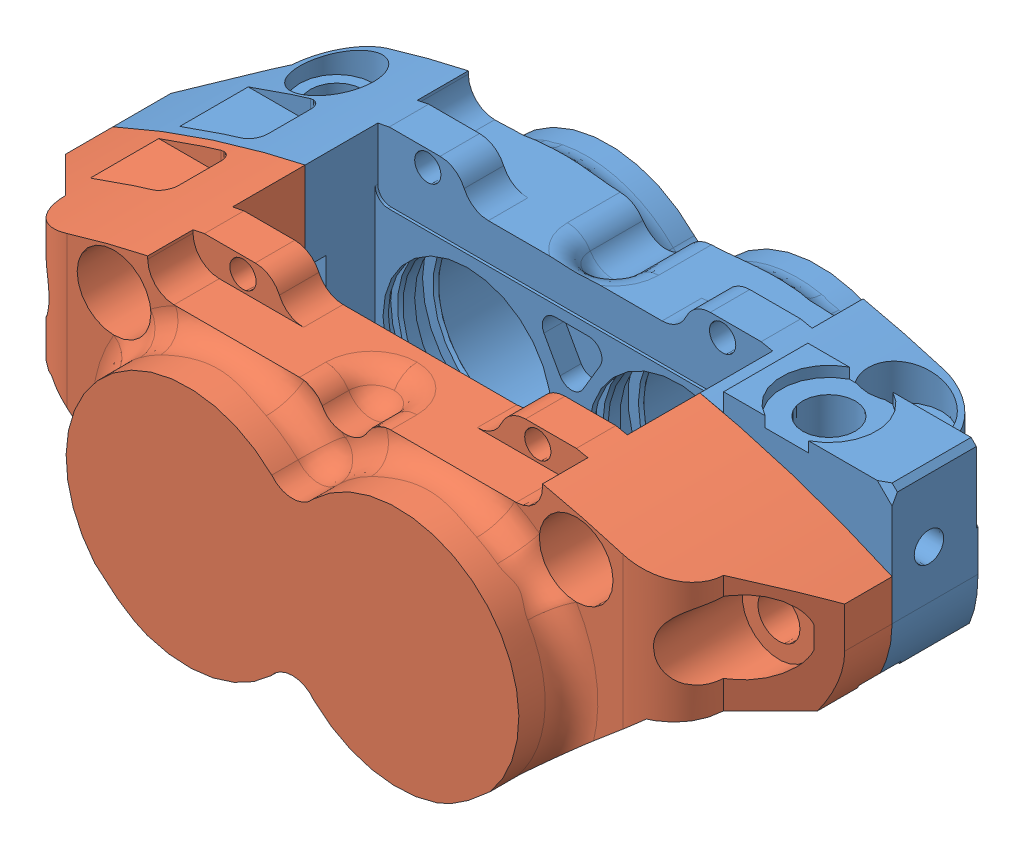
SolidWorks assembly Assemblage1, configuration Défaut. Lengths in mm.
Overall size (148 56.5 79.9).
2 component instances, 2 part files, 3 mates.
Components (placement in the parent):
- coté gauche-1: coté gauche [Défaut] at (-14.402 -5.9455 106) size (148 56.5 40)
- coté droit-1: coté droit [coté droit] at (-14.402 -5.9455 106) size (148 54.5 39.9)
Mates (geometry in assembly coordinates):
- Coaxiale1: concentric anti-aligned: cylinder of coté gauche-1 through (-58.2097 15.322 106) axis (0 0 1) radius 2.5; cylinder of coté droit-1 through (-58.2097 15.322 190) axis (0 0 -1) radius 2.5
- Coaxiale2: concentric aligned: cylinder of coté gauche-1 through (-74.1097 8.622 130) axis (0 0 1) radius 4; cylinder of coté droit-1 through (-74.1097 8.622 58) axis (0 0 1) radius 4
- Coïncidente1: coincident anti-aligned: plane of coté gauche-1 through (-14.402 -5.9455 148) normal (0 0 1); plane of coté droit-1 through (-14.402 -5.9455 148) normal (0 0 -1)
